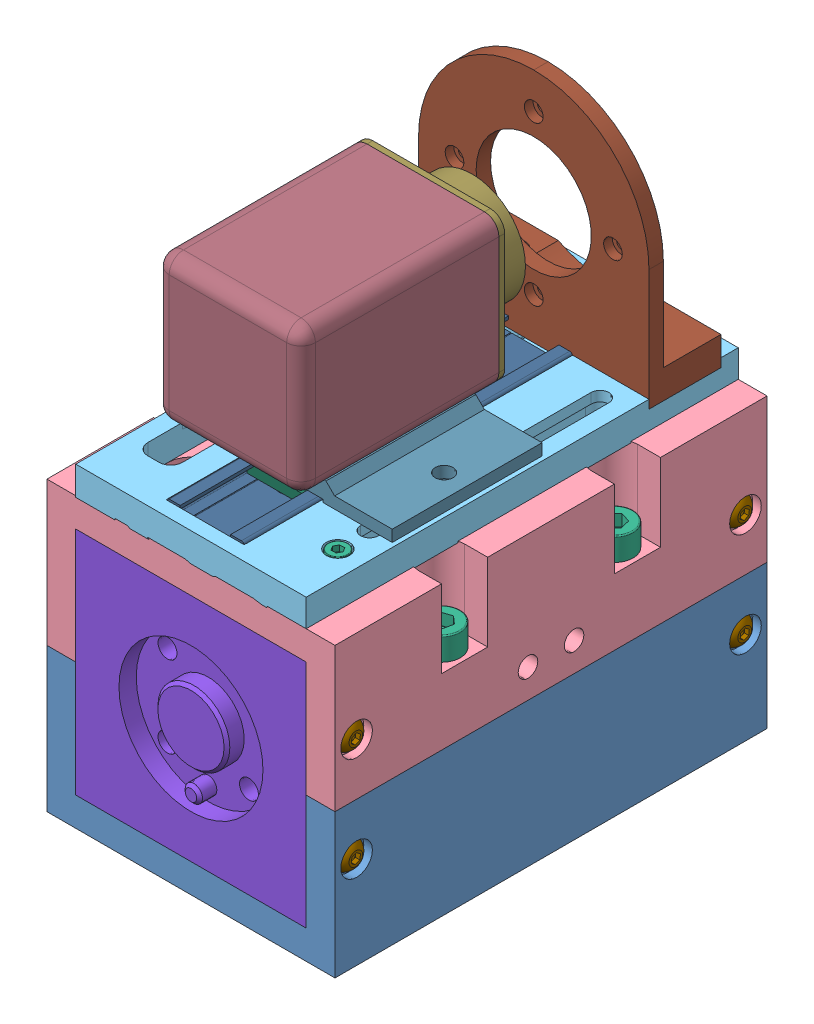
SolidWorks assembly Conjunto, configuration Default. Lengths in mm.
Overall size (100.24 188.5 226.33).
43 component instances, 15 part files, 84 mates.
Components (placement in the parent):
- Estrutura_bottom-1: Estrutura_bottom [Default] at (-19.0494 -42.1119 38.6623) size (100 50 150)
- PCB-1: PCB [Default] at (-19.0494 13.3881 -36.3377) size (66 1.5 67)
- Slotted Cheese Head Screw_ISO-1: Slotted Cheese Head Screw_ISO [ISO 1207 - M3 x 8 --- 8C] at (10.4506 11.3881 -6.3377) x (0 1 0) z (-0.0255 0 0.999675) size (10.01 5.5 5.5)
- Slotted Cheese Head Screw_ISO-2: Slotted Cheese Head Screw_ISO [ISO 1207 - M3 x 8 --- 8C] at (-48.5494 11.3881 -66.3377) x (0 1 0) z (0.247102 0 -0.96899) size (10.01 5.5 5.5)
- Slotted Cheese Head Screw_ISO-3: Slotted Cheese Head Screw_ISO [ISO 1207 - M3 x 8 --- 8C] at (-48.5494 11.3881 -6.3377) x (0 1 0) z (0.728633 0 -0.684905) size (10.01 5.5 5.5)
- Slotted Cheese Head Screw_ISO-4: Slotted Cheese Head Screw_ISO [ISO 1207 - M3 x 8 --- 8C] at (10.4506 11.3881 -66.3377) x (0 1 0) z (0.99688 0 -0.078934) size (10.01 5.5 5.5)
- Estrutura_top-1: Estrutura_top [Default] at (-19.0494 47.8881 38.6623) x (-1 0 0) z (0 0 1) size (100 50 150)
- Apoio_sistema_visao-1: Apoio_sistema_visao [Default] at (-19.0494 47.3881 -36.3377) x (-1 0 0) z (0 0 -1) size (80 10 150)
- Socket Head Cap Screw_ISO-1: Socket Head Cap Screw_ISO [ISO 4762 M4 x 16 --- 16C] at (11.9506 57.3881 18.6623) x (0 -1 0) z (0.024629 0 0.999697) size (20 7 7)
- Socket Head Cap Screw_ISO-3: Socket Head Cap Screw_ISO [ISO 4762 M4 x 12 --- 12C] at (-50.0494 54.3881 -93.3377) x (0 -1 0) z (-0.124962 0 0.992162) size (16 7 7)
- robot_fix-1: robot_fix [Default] at (-19.0494 -2.1119 -96.3377) size (80 80 102.04)
- Acoplamento_robot_50mm-1: Acoplamento_robot_50mm [Default] at (-19.0494 -2.1119 23.6623) size (80 80 89.49)
- Socket Head Cap Screw_ISO-4: Socket Head Cap Screw_ISO [ISO 4762 M8 x 40 --- 28C] at (22.9506 28.8881 -6.3377) x (0 -1 0) z (-0.319372 0 -0.947629) size (48 13 13)
- Socket Head Cap Screw_ISO-5: Socket Head Cap Screw_ISO [ISO 4762 M8 x 40 --- 28C] at (-61.0494 28.8881 -6.3377) x (0 -1 0) z (0.245168 0 0.96948) size (48 13 13)
- Socket Head Cap Screw_ISO-6: Socket Head Cap Screw_ISO [ISO 4762 M8 x 40 --- 28C] at (22.9506 28.8881 -66.3377) x (0 -1 0) z (0.971794 0 -0.235832) size (48 13 13)
- Socket Head Cap Screw_ISO-7: Socket Head Cap Screw_ISO [ISO 4762 M8 x 40 --- 28C] at (-61.0494 28.8881 -66.3377) x (0 -1 0) z (0 0 1) size (48 13 13)
- Socket Button Head Screw_ISO-1: Socket Button Head Screw_ISO [ISO 7380 - M5 x 16 --- 16C] at (-68.7994 15.8881 -103.8377) x (1 0 0) z (0 -0.335428 0.942066) size (18.75 9.5 9.5)
- Socket Button Head Screw_ISO-2: Socket Button Head Screw_ISO [ISO 7380 - M5 x 16 --- 16C] at (-68.7994 -20.1119 -103.8377) size (18.75 9.5 9.5)
- Socket Button Head Screw_ISO-3: Socket Button Head Screw_ISO [ISO 7380 - M5 x 16 --- 16C] at (-68.7994 -20.1119 31.1623) size (18.75 9.5 9.5)
- Socket Button Head Screw_ISO-4: Socket Button Head Screw_ISO [ISO 7380 - M5 x 16 --- 16C] at (-68.7994 15.8881 31.1623) size (18.75 9.5 9.5)
- Socket Button Head Screw_ISO-5: Socket Button Head Screw_ISO [ISO 7380 - M5 x 16 --- 16C] at (30.7006 -20.1119 -103.8377) x (-1 0 0) z (0 -0.924225 -0.381849) size (18.75 9.5 9.5)
- Socket Button Head Screw_ISO-6: Socket Button Head Screw_ISO [ISO 7380 - M5 x 16 --- 16C] at (30.7006 15.8881 31.1623) x (-1 0 0) z (0 -0.924225 -0.381849) size (18.75 9.5 9.5)
- Socket Button Head Screw_ISO-7: Socket Button Head Screw_ISO [ISO 7380 - M5 x 16 --- 16C] at (30.7006 15.8881 -103.8377) x (-1 0 0) z (0 -0.924225 -0.381849) size (18.75 9.5 9.5)
- Socket Button Head Screw_ISO-8: Socket Button Head Screw_ISO [ISO 7380 - M5 x 16 --- 16C] at (30.7006 -20.1119 31.1623) x (-1 0 0) z (0 -0.924225 -0.381849) size (18.75 9.5 9.5)
- Socket Button Head Screw_ISO-9: Socket Button Head Screw_ISO [ISO 7380 - M5 x 16 --- 16C] at (-1.0494 -49.8619 31.1623) x (0 1 0) z (-0.188342 0 0.982104) size (18.75 9.5 9.5)
- Socket Button Head Screw_ISO-10: Socket Button Head Screw_ISO [ISO 7380 - M5 x 16 --- 16C] at (-37.0494 -49.8619 -103.8377) x (0 1 0) z (-0.319462 0 0.947599) size (18.75 9.5 9.5)
- Socket Button Head Screw_ISO-11: Socket Button Head Screw_ISO [ISO 7380 - M5 x 16 --- 16C] at (-1.0494 -49.8619 -103.8377) x (0 1 0) z (0.485773 0 0.874085) size (18.75 9.5 9.5)
- Socket Button Head Screw_ISO-12: Socket Button Head Screw_ISO [ISO 7380 - M5 x 16 --- 16C] at (-37.0494 -49.8619 31.1623) x (0 1 0) z (-0.266822 0 0.963746) size (18.75 9.5 9.5)
- Socket Button Head Screw_ISO-13: Socket Button Head Screw_ISO [ISO 7380 - M5 x 16 --- 16C] at (-1.0494 47.6381 -103.8377) x (0 -1 0) z (0 0 1) size (18.75 9.5 9.5)
- Socket Button Head Screw_ISO-14: Socket Button Head Screw_ISO [ISO 7380 - M5 x 16 --- 16C] at (-37.1275 47.6381 -103.4453) x (0 -1 0) z (0 0 1) size (18.75 9.5 9.5)
- Socket Button Head Screw_ISO-15: Socket Button Head Screw_ISO [ISO 7380 - M5 x 16 --- 16C] at (-37.0494 47.6381 31.1623) x (0 -1 0) z (0 0 1) size (18.75 9.5 9.5)
- Socket Button Head Screw_ISO-16: Socket Button Head Screw_ISO [ISO 7380 - M5 x 16 --- 16C] at (-1.0494 47.6381 31.1623) x (0 -1 0) z (0 0 1) size (18.75 9.5 9.5)
- Calha_deslizante_27mm-1: Calha_deslizante_27mm [Default] at (-19.0494 49.3881 33.6623) x (1 0 0) z (0 1 0) size (27 114 8.7)
- Apoio_iluminacaoLEDs-1: Apoio_iluminacaoLEDs [Default] at (-19.0494 96.3881 -85.3377) x (-1 0 0) z (0 0 -1) size (80 82 83.14)
- Camara-1: Camara [Default] at (-9.1145 86.544 -26.3473) x (-1 0 0) z (0 0 -1) size (50.8 57.8 84.8)
  - Encaixe_lente-1: Encaixe_lente [Default] at (9.935 10.7441 16.5114) size (50.8 50.8 16.1)
  - Carapaca-1: Carapaca [Default] at (9.935 10.7441 -17.8386) size (50.8 57.8 68.7)
- Apoio_camara_27mm-1: Apoio_camara_27mm [Default] at (-19.0494 57.8881 7.7847) size (54 7 52)
- Carro_deslizante_27mm-1: Carro_deslizante_27mm [Default] at (-19.0494 49.3881 -12.2153) x (1 0 0) z (0 1 0) size (23.9 40 5.35)
- Socket Button Head Screw_ISO-17: Socket Button Head Screw_ISO [ISO 7380 - M6 x 10 --- 10C] at (-19.0494 59.4881 -34.2153) x (0 1 0) z (-0.986695 0 0.162581) size (13.3 10.5 10.5)
- Socket Button Head Screw_ISO-18: Socket Button Head Screw_ISO [ISO 7380 - M6 x 10 --- 10C] at (-19.0494 59.4881 -12.2153) x (0 1 0) z (-0.817728 0 0.575605) size (13.3 10.5 10.5)
- Socket Button Head Screw_ISO-19: Socket Button Head Screw_ISO [ISO 7380 - M4 x 8 --- 8C] at (-19.0494 55.1881 -22.2153) x (0 1 0) z (-0.967097 0 0.254409) size (10.2 7.6 7.6)
- Socket Button Head Screw_ISO-20: Socket Button Head Screw_ISO [ISO 7380 - M4 x 8 --- 8C] at (-19.0494 55.1881 -2.2153) x (0 1 0) z (-0.934565 0 0.355792) size (10.2 7.6 7.6)
Mates (geometry in assembly coordinates):
- Concentric7: concentric anti-aligned: cylinder of PCB-1 through (-48.5494 14.8881 -6.3377) axis (0 1 0) radius 1.75; cylinder of Estrutura_top-1 through (-48.5494 14.8881 -6.3377) axis (0 -1 0) radius 1.25
- Concentric8: concentric anti-aligned: cylinder of PCB-1 through (10.4506 14.8881 -66.3377) axis (0 1 0) radius 1.75; cylinder of Estrutura_top-1 through (10.4506 14.8881 -66.3377) axis (0 -1 0) radius 1.25
- Coincident7: coincident anti-aligned: plane of PCB-1 through (13.9506 14.8881 -2.8377) normal (0 1 0); plane of Estrutura_top-1 through (16.9506 14.8881 -59.6294) normal (0 -1 0)
- Concentric9: concentric aligned: cylinder of Slotted Cheese Head Screw_ISO-4 through (10.4506 -14.0119 -66.3377) axis (0 -1 0) radius 1.5; cylinder of Estrutura_top-1 through (10.4506 14.8881 -66.3377) axis (0 -1 0) radius 1.25
- Concentric10: concentric aligned: cylinder of Slotted Cheese Head Screw_ISO-2 through (-48.5494 -14.0119 -66.3377) axis (0 -1 0) radius 1.5; cylinder of Estrutura_top-1 through (-48.5494 14.8881 -66.3377) axis (0 -1 0) radius 1.25
- Concentric11: concentric aligned: cylinder of Slotted Cheese Head Screw_ISO-3 through (-48.5494 -14.0119 -6.3377) axis (0 -1 0) radius 1.5; cylinder of Estrutura_top-1 through (-48.5494 14.8881 -6.3377) axis (0 -1 0) radius 1.25
- Concentric12: concentric aligned: cylinder of Slotted Cheese Head Screw_ISO-1 through (10.4506 -14.0119 -6.3377) axis (0 -1 0) radius 1.5; cylinder of Estrutura_top-1 through (10.4506 14.8881 -6.3377) axis (0 -1 0) radius 1.25
- Coincident8: coincident anti-aligned: plane of PCB-1 through (13.9506 13.3881 -2.8377) normal (0 -1 0); plane of Slotted Cheese Head Screw_ISO-2 through (-47.0959 13.3881 -65.967) normal (0 1 0)
- Coincident9: coincident anti-aligned: plane of PCB-1 through (13.9506 13.3881 -2.8377) normal (0 -1 0); plane of Slotted Cheese Head Screw_ISO-4 through (10.569 13.3881 -64.8423) normal (0 1 0)
- Coincident10: coincident anti-aligned: plane of PCB-1 through (13.9506 13.3881 -2.8377) normal (0 -1 0); plane of Slotted Cheese Head Screw_ISO-1 through (8.9511 13.3881 -6.3759) normal (0 1 0)
- Coincident11: coincident anti-aligned: plane of PCB-1 through (13.9506 13.3881 -2.8377) normal (0 -1 0); plane of Slotted Cheese Head Screw_ISO-3 through (-47.5221 13.3881 -5.2447) normal (0 1 0)
- Concentric13: concentric aligned: cylinder of Estrutura_bottom-1 through (-61.0494 -2.1119 -6.3377) axis (0 1 0) radius 3.4; cylinder of Estrutura_top-1 through (-61.0494 20.8881 -6.3377) axis (0 1 0) radius 4
- Concentric14: concentric aligned: circle of Estrutura_bottom-1; cylinder of Estrutura_top-1 through (22.9506 20.8881 -66.3377) axis (0 1 0) radius 4
- Coincident12: coincident anti-aligned: plane of Estrutura_bottom-1 through (20.9506 -2.1119 38.6623) normal (0 1 0); plane of Estrutura_top-1 through (20.9506 -2.1119 -111.3377) normal (0 -1 0)
- Concentric17: concentric aligned: cylinder of Estrutura_top-1 through (11.9506 47.8881 18.6623) axis (0 1 0) radius 1.65; cylinder of Socket Head Cap Screw_ISO-1 through (11.9506 89.1381 18.6623) axis (0 1 0) radius 2
- Coincident15: coincident anti-aligned: plane of Apoio_sistema_visao-1 through (9.5506 53.3881 18.6623) normal (0 1 0); plane of Socket Head Cap Screw_ISO-1 through (15.4495 53.3881 18.5761) normal (0 -1 0)
- Concentric19: concentric aligned: cylinder of Estrutura_top-1 through (-50.0494 47.8881 -93.3377) axis (0 1 0) radius 1.65; cylinder of Socket Head Cap Screw_ISO-3 through (-50.0494 86.1381 -93.3377) axis (0 1 0) radius 2
- Coincident16: coincident anti-aligned: plane of Apoio_sistema_visao-1 through (-52.4494 50.3881 -91.3377) normal (0 1 0); plane of Socket Head Cap Screw_ISO-3 through (-46.5768 50.3881 -92.9003) normal (0 -1 0)
- Concentric20: concentric aligned: cylinder of Estrutura_top-1 through (-1.0494 47.8881 -103.8377) axis (0 1 0) radius 2.75; cylinder of robot_fix-1 through (-1.0494 37.8881 -103.8377) axis (0 1 0) radius 2.1
- Concentric21: concentric aligned: cylinder of Estrutura_top-1 through (30.9506 15.8881 -103.8377) axis (1 0 0) radius 2.75; cylinder of robot_fix-1 through (20.9506 15.8881 -103.8377) axis (1 0 0) radius 2.1
- Concentric22: concentric aligned: cylinder of Estrutura_top-1 through (30.9506 15.8881 31.1623) axis (1 0 0) radius 2.75; cylinder of Acoplamento_robot_50mm-1 through (20.9506 15.8881 31.1623) axis (1 0 0) radius 2.1
- Concentric23: concentric aligned: cylinder of Estrutura_top-1 through (-37.0494 47.8881 31.1623) axis (0 1 0) radius 2.75; cylinder of Acoplamento_robot_50mm-1 through (-37.0494 37.8881 31.1623) axis (0 1 0) radius 2.1
- Concentric24: concentric aligned: cylinder of Estrutura_top-1 through (-61.0494 20.8881 -6.3377) axis (0 1 0) radius 4; cylinder of Socket Head Cap Screw_ISO-5 through (-61.0494 60.6381 -6.3377) axis (0 1 0) radius 4
- Concentric25: concentric aligned: cylinder of Estrutura_top-1 through (22.9506 20.8881 -6.3377) axis (0 1 0) radius 4; cylinder of Socket Head Cap Screw_ISO-4 through (22.9506 60.6381 -6.3377) axis (0 1 0) radius 4
- Concentric26: concentric aligned: cylinder of Estrutura_top-1 through (22.9506 20.8881 -66.3377) axis (0 1 0) radius 4; cylinder of Socket Head Cap Screw_ISO-6 through (22.9506 60.6381 -66.3377) axis (0 1 0) radius 4
- Concentric27: concentric aligned: cylinder of Estrutura_top-1 through (-61.0494 20.8881 -66.3377) axis (0 1 0) radius 4; cylinder of Socket Head Cap Screw_ISO-7 through (-61.0494 60.6381 -66.3377) axis (0 1 0) radius 4
- Coincident17: coincident anti-aligned: plane of Estrutura_top-1 through (-61.0494 20.8881 -6.3377) normal (0 1 0); plane of Socket Head Cap Screw_ISO-5 through (-54.7478 20.8881 -7.9312) normal (0 -1 0)
- Coincident18: coincident anti-aligned: plane of Estrutura_top-1 through (-61.0494 20.8881 -66.3377) normal (0 1 0); plane of Socket Head Cap Screw_ISO-7 through (-54.5494 20.8881 -66.3377) normal (0 -1 0)
- Coincident19: coincident anti-aligned: plane of Estrutura_top-1 through (22.9506 20.8881 -66.3377) normal (0 1 0); plane of Socket Head Cap Screw_ISO-6 through (21.4177 20.8881 -72.6543) normal (0 -1 0)
- Coincident20: coincident anti-aligned: plane of Estrutura_top-1 through (22.9506 20.8881 -6.3377) normal (0 1 0); plane of Socket Head Cap Screw_ISO-4 through (16.791 20.8881 -4.2617) normal (0 -1 0)
- Concentric28: concentric aligned: cylinder of Acoplamento_robot_50mm-1 through (-1.0494 37.8881 31.1623) axis (0 1 0) radius 2.1; cylinder of Socket Button Head Screw_ISO-16 through (-1.0494 47.6381 31.1623) axis (0 1 0) radius 2.5
- Concentric29: concentric aligned: cylinder of Acoplamento_robot_50mm-1 through (-37.0494 37.8881 31.1623) axis (0 1 0) radius 2.1; cylinder of Socket Button Head Screw_ISO-15 through (-37.0494 47.6381 31.1623) axis (0 1 0) radius 2.5
- Tangent2: tangent aligned: cylinder of Socket Button Head Screw_ISO-14 through (-37.1275 47.6381 -103.4453) axis (0 1 0) radius 2.5; cylinder of robot_fix-1 through (-37.0494 37.8881 -103.8377) axis (0 1 0) radius 2.1
- Concentric30: concentric aligned: cylinder of robot_fix-1 through (-1.0494 37.8881 -103.8377) axis (0 1 0) radius 2.1; cylinder of Socket Button Head Screw_ISO-13 through (-1.0494 47.6381 -103.8377) axis (0 1 0) radius 2.5
- Coincident21: coincident anti-aligned: plane of Estrutura_top-1 through (-3.7994 44.8881 -103.8377) normal (0 1 0); plane of Socket Button Head Screw_ISO-13 through (1.4506 44.8881 -103.8377) normal (0 -1 0)
- Coincident22: coincident anti-aligned: plane of Estrutura_top-1 through (-39.7994 44.8881 -103.8377) normal (0 1 0); plane of Socket Button Head Screw_ISO-14 through (-34.6275 44.8881 -103.4453) normal (0 -1 0)
- Coincident23: coincident anti-aligned: plane of Estrutura_top-1 through (-39.7994 44.8881 31.1623) normal (0 1 0); plane of Socket Button Head Screw_ISO-15 through (-34.5494 44.8881 31.1623) normal (0 -1 0)
- Coincident24: coincident anti-aligned: plane of Estrutura_top-1 through (-3.7994 44.8881 31.1623) normal (0 1 0); plane of Socket Button Head Screw_ISO-16 through (1.4506 44.8881 31.1623) normal (0 -1 0)
- Concentric31: concentric aligned: cylinder of robot_fix-1 through (20.9506 -20.1119 -103.8377) axis (1 0 0) radius 2.1; cylinder of Socket Button Head Screw_ISO-5 through (30.7006 -20.1119 -103.8377) axis (1 0 0) radius 2.5
- Concentric32: concentric aligned: cylinder of robot_fix-1 through (20.9506 15.8881 -103.8377) axis (1 0 0) radius 2.1; cylinder of Socket Button Head Screw_ISO-7 through (30.7006 15.8881 -103.8377) axis (1 0 0) radius 2.5
- Concentric33: concentric aligned: cylinder of Acoplamento_robot_50mm-1 through (20.9506 -20.1119 31.1623) axis (1 0 0) radius 2.1; cylinder of Socket Button Head Screw_ISO-8 through (30.7006 -20.1119 31.1623) axis (1 0 0) radius 2.5
- Concentric34: concentric aligned: cylinder of Acoplamento_robot_50mm-1 through (20.9506 15.8881 31.1623) axis (1 0 0) radius 2.1; cylinder of Socket Button Head Screw_ISO-6 through (30.7006 15.8881 31.1623) axis (1 0 0) radius 2.5
- Coincident25: coincident anti-aligned: plane of Estrutura_top-1 through (27.9506 13.1381 31.1623) normal (1 0 0); plane of Socket Button Head Screw_ISO-6 through (27.9506 16.8427 28.8518) normal (-1 0 0)
- Coincident26: coincident anti-aligned: plane of Estrutura_bottom-1 through (27.9506 -17.3619 31.1623) normal (1 0 0); plane of Socket Button Head Screw_ISO-8 through (27.9506 -19.1573 28.8518) normal (-1 0 0)
- Coincident27: coincident anti-aligned: plane of Estrutura_bottom-1 through (27.9506 -17.3619 -103.8377) normal (1 0 0); plane of Socket Button Head Screw_ISO-5 through (27.9506 -19.1573 -106.1482) normal (-1 0 0)
- Coincident28: coincident anti-aligned: plane of Estrutura_top-1 through (27.9506 13.1381 -103.8377) normal (1 0 0); plane of Socket Button Head Screw_ISO-7 through (27.9506 16.8427 -106.1482) normal (-1 0 0)
- Concentric35: concentric aligned: cylinder of Acoplamento_robot_50mm-1 through (-59.0494 15.8881 31.1623) axis (-1 0 0) radius 2.1; cylinder of Socket Button Head Screw_ISO-4 through (-68.7994 15.8881 31.1623) axis (-1 0 0) radius 2.5
- Concentric36: concentric aligned: cylinder of Acoplamento_robot_50mm-1 through (-59.0494 -20.1119 31.1623) axis (-1 0 0) radius 2.1; cylinder of Socket Button Head Screw_ISO-3 through (-68.7994 -20.1119 31.1623) axis (-1 0 0) radius 2.5
- Concentric37: concentric aligned: cylinder of robot_fix-1 through (-59.0494 -20.1119 -103.8377) axis (-1 0 0) radius 2.1; cylinder of Socket Button Head Screw_ISO-2 through (-68.7994 -20.1119 -103.8377) axis (-1 0 0) radius 2.5
- Concentric38: concentric aligned: cylinder of robot_fix-1 through (-59.0494 15.8881 -103.8377) axis (-1 0 0) radius 2.1; cylinder of Socket Button Head Screw_ISO-1 through (-68.7994 15.8881 -103.8377) axis (-1 0 0) radius 2.5
- Coincident29: coincident anti-aligned: plane of Estrutura_bottom-1 through (-66.0494 -17.3619 -103.8377) normal (-1 0 0); plane of Socket Button Head Screw_ISO-2 through (-66.0494 -17.6119 -103.8377) normal (1 0 0)
- Coincident30: coincident anti-aligned: plane of Estrutura_bottom-1 through (-66.0494 -17.3619 31.1623) normal (-1 0 0); plane of Socket Button Head Screw_ISO-3 through (-66.0494 -17.6119 31.1623) normal (1 0 0)
- Coincident31: coincident anti-aligned: plane of Estrutura_top-1 through (-66.0494 13.1381 31.1623) normal (-1 0 0); plane of Socket Button Head Screw_ISO-4 through (-66.0494 18.3881 31.1623) normal (1 0 0)
- Coincident32: coincident anti-aligned: plane of Estrutura_top-1 through (-66.0494 13.1381 -103.8377) normal (-1 0 0); plane of Socket Button Head Screw_ISO-1 through (-66.0494 18.2432 -102.9991) normal (1 0 0)
- Concentric39: concentric aligned: cylinder of Acoplamento_robot_50mm-1 through (-1.0494 -42.1119 31.1623) axis (0 -1 0) radius 2.1; cylinder of Socket Button Head Screw_ISO-9 through (-1.0494 -49.8619 31.1623) axis (0 -1 0) radius 2.5
- Concentric40: concentric aligned: cylinder of Acoplamento_robot_50mm-1 through (-37.0494 -42.1119 31.1623) axis (0 -1 0) radius 2.1; cylinder of Socket Button Head Screw_ISO-12 through (-37.0494 -49.8619 31.1623) axis (0 -1 0) radius 2.5
- Concentric41: concentric aligned: cylinder of robot_fix-1 through (-1.0494 -42.1119 -103.8377) axis (0 -1 0) radius 2.1; cylinder of Socket Button Head Screw_ISO-11 through (-1.0494 -49.8619 -103.8377) axis (0 -1 0) radius 2.5
- Concentric42: concentric aligned: cylinder of robot_fix-1 through (-37.0494 -42.1119 -103.8377) axis (0 -1 0) radius 2.1; cylinder of Socket Button Head Screw_ISO-10 through (-37.0494 -49.8619 -103.8377) axis (0 -1 0) radius 2.5
- Coincident33: coincident anti-aligned: plane of Estrutura_bottom-1 through (1.7006 -47.1119 31.1623) normal (0 -1 0); plane of Socket Button Head Screw_ISO-9 through (-3.5047 -47.1119 30.6915) normal (0 1 0)
- Coincident34: coincident anti-aligned: plane of Estrutura_bottom-1 through (-34.2994 -47.1119 31.1623) normal (0 -1 0); plane of Socket Button Head Screw_ISO-12 through (-39.4588 -47.1119 30.4953) normal (0 1 0)
- Coincident35: coincident anti-aligned: plane of Estrutura_bottom-1 through (1.7006 -47.1119 -103.8377) normal (0 -1 0); plane of Socket Button Head Screw_ISO-11 through (-3.2346 -47.1119 -102.6232) normal (0 1 0)
- Coincident36: coincident anti-aligned: plane of Estrutura_bottom-1 through (-34.2994 -47.1119 -103.8377) normal (0 -1 0); plane of Socket Button Head Screw_ISO-10 through (-39.4184 -47.1119 -104.6363) normal (0 1 0)
- Coincident37: coincident anti-aligned: plane of Apoio_sistema_visao-1 through (-5.5494 49.3881 33.6623) normal (0 1 0); plane of Calha_deslizante_27mm-1 through (-19.0494 49.3881 33.6623) normal (0 -1 0)
- Coincident38: coincident aligned: plane of Apoio_sistema_visao-1 through (20.9506 54.3881 -80.3377) normal (0 0 -1); plane of Calha_deslizante_27mm-1 through (-29.8494 50.6881 -80.3377) normal (0 0 -1)
- Width1: width: plane of Apoio_sistema_visao-1 through (-5.5494 49.8881 -80.3377) normal (-1 0 0); plane of Apoio_sistema_visao-1 through (-32.5494 49.8881 -80.3377) normal (1 0 0); plane of Calha_deslizante_27mm-1 through (-5.5494 53.3881 33.6623) normal (1 0 0); plane of Calha_deslizante_27mm-1 through (-32.5494 57.0881 33.6623) normal (-1 0 0)
- Coincident39: coincident anti-aligned: plane of Apoio_sistema_visao-1 through (20.9506 54.3881 -80.3377) normal (0 0 -1); plane of Apoio_iluminacaoLEDs-1 through (20.9506 54.3881 -80.3377) normal (0 0 1)
- Coincident40: coincident aligned: plane of Apoio_sistema_visao-1 through (20.9506 57.3881 38.6623) normal (1 0 0); plane of Apoio_iluminacaoLEDs-1 through (20.9506 136.3881 -80.3377) normal (1 0 0)
- Coincident41: coincident anti-aligned: plane of Apoio_sistema_visao-1 through (20.9506 54.3881 -105.3377) normal (0 1 0); plane of Apoio_iluminacaoLEDs-1 through (20.9506 54.3881 -80.3377) normal (0 -1 0)
- Concentric44: concentric aligned: cylinder of Camara-1/Carapaca-1 through (-19.0494 64.8881 -34.2153) axis (0 -1 0) radius 2.5; cylinder of Apoio_camara_27mm-1 through (-19.0494 58.8881 -34.2153) axis (0 -1 0) radius 3.5
- Concentric45: concentric aligned: cylinder of Camara-1/Carapaca-1 through (-19.0494 64.8881 -12.2153) axis (0 -1 0) radius 2.5; cylinder of Apoio_camara_27mm-1 through (-19.0494 58.8881 -12.2153) axis (0 -1 0) radius 3.5
- Coincident42: coincident anti-aligned: plane of Camara-1/Carapaca-1 through (-6.5494 64.8881 -7.1587) normal (0 -1 0); plane of Apoio_camara_27mm-1 through (-0.0494 64.8881 -32.2153) normal (0 1 0)
- Concentric46: concentric aligned: cylinder of Camara-1/Carapaca-1 through (-19.0494 64.8881 -34.2153) axis (0 -1 0) radius 2.5; cylinder of Socket Button Head Screw_ISO-17 through (-19.0494 59.4881 -34.2153) axis (0 -1 0) radius 3
- Concentric47: concentric aligned: cylinder of Camara-1/Carapaca-1 through (-19.0494 64.8881 -12.2153) axis (0 -1 0) radius 2.5; cylinder of Socket Button Head Screw_ISO-18 through (-19.0494 59.4881 -12.2153) axis (0 -1 0) radius 3
- Coincident43: coincident anti-aligned: plane of Apoio_camara_27mm-1 through (-15.5494 62.7881 -34.2153) normal (0 -1 0); plane of Socket Button Head Screw_ISO-17 through (-19.5372 62.7881 -37.1754) normal (0 1 0)
- Coincident44: coincident anti-aligned: plane of Apoio_camara_27mm-1 through (-15.5494 62.7881 -12.2153) normal (0 -1 0); plane of Socket Button Head Screw_ISO-18 through (-20.7762 62.7881 -14.6685) normal (0 1 0)
- Concentric48: concentric anti-aligned: cylinder of Apoio_camara_27mm-1 through (-19.0494 58.8881 -22.2153) axis (0 -1 0) radius 1.65; cylinder of Carro_deslizante_27mm-1 through (-19.0494 58.7881 -22.2153) axis (0 1 0) radius 2.25
- Concentric49: concentric anti-aligned: cylinder of Apoio_camara_27mm-1 through (-19.0494 58.8881 -2.2153) axis (0 -1 0) radius 1.65; cylinder of Carro_deslizante_27mm-1 through (-19.0494 58.7881 -2.2153) axis (0 1 0) radius 2.25
- Coincident45: coincident anti-aligned: plane of Apoio_camara_27mm-1 through (-34.0494 58.8881 -32.2153) normal (0 -1 0); plane of Carro_deslizante_27mm-1 through (-12.5544 58.8881 2.8347) normal (0 1 0)
- Concentric50: concentric aligned: cylinder of Apoio_camara_27mm-1 through (-19.0494 58.8881 -22.2153) axis (0 -1 0) radius 1.65; cylinder of Socket Button Head Screw_ISO-19 through (-19.0494 55.1881 -22.2153) axis (0 -1 0) radius 2
- Concentric51: concentric aligned: cylinder of Apoio_camara_27mm-1 through (-19.0494 58.8881 -2.2153) axis (0 -1 0) radius 1.65; cylinder of Socket Button Head Screw_ISO-20 through (-19.0494 55.1881 -2.2153) axis (0 -1 0) radius 2
- Coincident46: coincident anti-aligned: plane of Carro_deslizante_27mm-1 through (-15.6994 57.3881 -22.2153) normal (0 -1 0); plane of Socket Button Head Screw_ISO-19 through (-19.5582 57.3881 -24.1495) normal (0 1 0)
- Coincident47: coincident anti-aligned: plane of Carro_deslizante_27mm-1 through (-15.6994 57.3881 -2.2153) normal (0 -1 0); plane of Socket Button Head Screw_ISO-20 through (-19.761 57.3881 -4.0845) normal (0 1 0)
- Width2: width: plane of Calha_deslizante_27mm-1 through (-31.0494 53.9881 33.6623) normal (1 0 0); plane of Calha_deslizante_27mm-1 through (-7.0494 56.4881 33.6623) normal (-1 0 0); plane of Carro_deslizante_27mm-1 through (-30.9994 56.3611 7.7847) normal (-1 0 0); plane of Carro_deslizante_27mm-1 through (-7.0994 54.1151 7.7847) normal (1 0 0)
- Width3: width: plane of Calha_deslizante_27mm-1 through (-30.5494 56.9881 33.6623) normal (0 -1 0); plane of Calha_deslizante_27mm-1 through (-26.9994 53.4881 33.6623) normal (0 1 0); plane of Carro_deslizante_27mm-1 through (-7.6764 56.9381 7.7847) normal (0 1 0); plane of Carro_deslizante_27mm-1 through (-13.8994 53.5381 7.7847) normal (0 -1 0)
